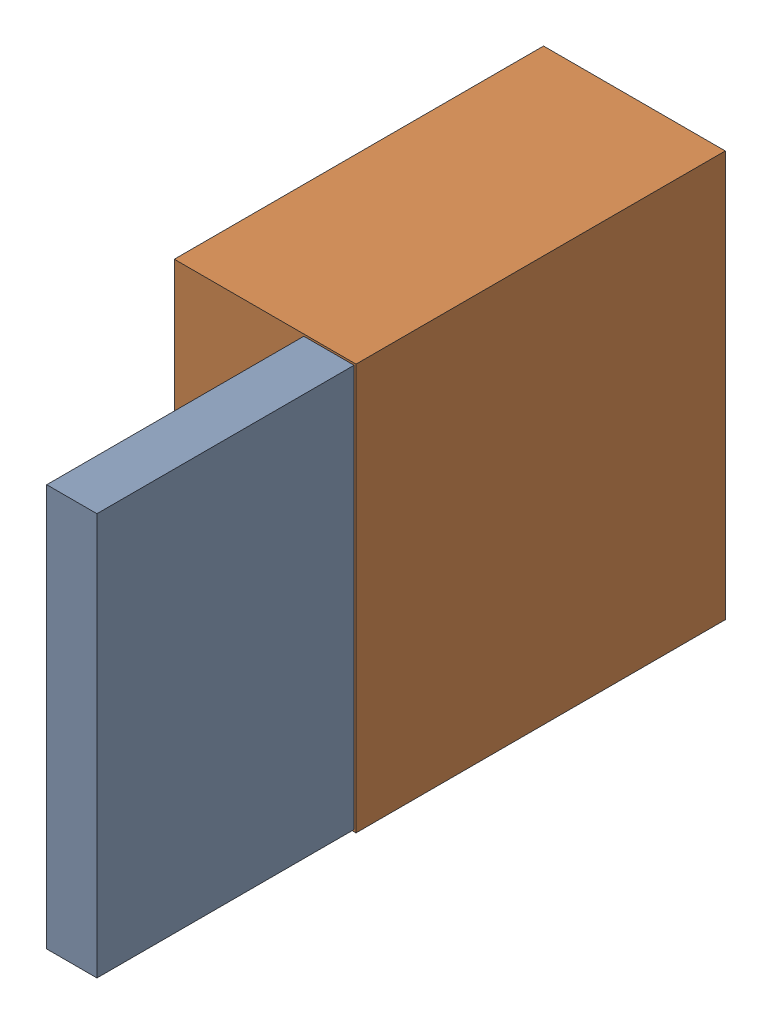
SolidWorks assembly U1_1, configuration Default. Lengths in mm.
Overall size (4.7 10.5 16.2).
4 component instances, 2 part files, 0 mates.
Components (placement in the parent):
- 1847993664_1-1: 1847993664_1 [Default] at (498.2 306.46 13.05) size (1.3 10.4 6.65)
  - Extruded_3-1: Extruded_3 [Default] at origin size (1.3 10.4 6.65)
- 1847994024_1-1: 1847994024_1 [Default] at (496.55 306.46 3.5) size (4.7 10.5 9.55)
  - Extruded_4-1: Extruded_4 [Default] at origin size (4.7 10.5 9.55)
